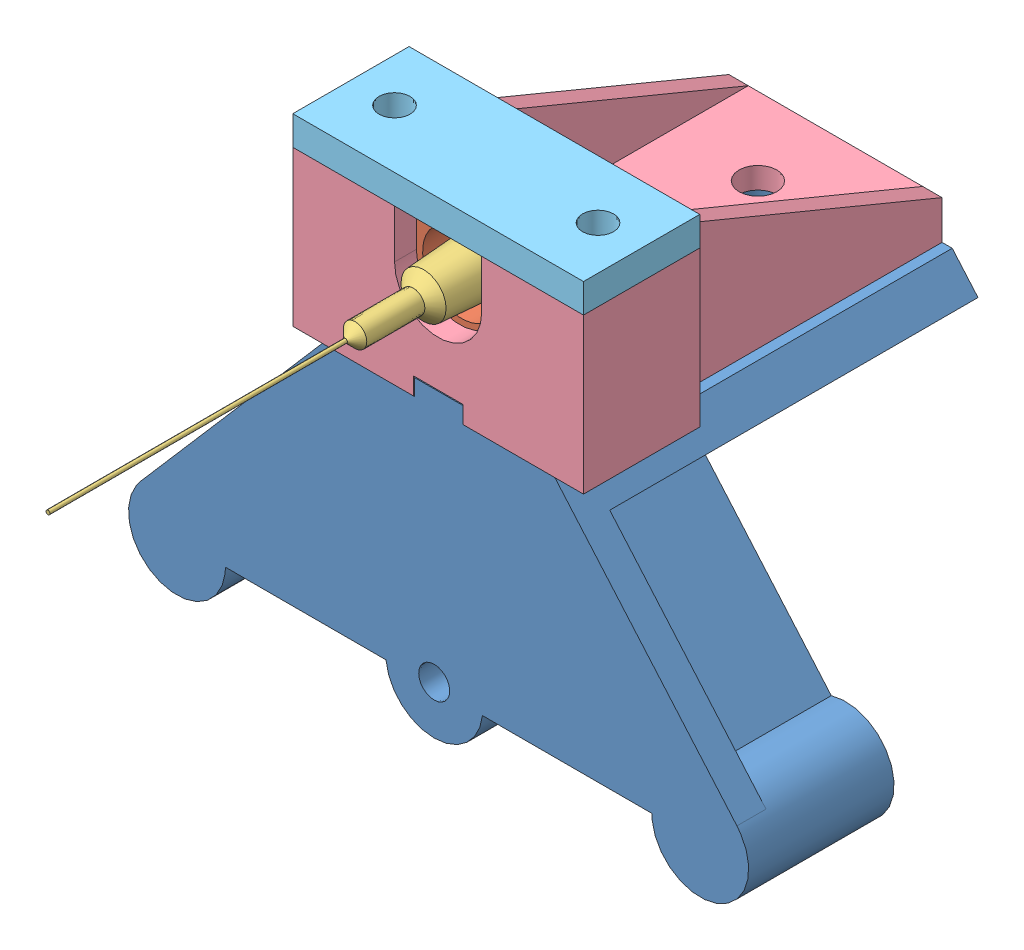
SolidWorks assembly Assem1, configuration Default. Lengths in mm.
Overall size (64 49 81.26).
5 component instances, 5 part files, 12 mates.
Components (placement in the parent):
- zsyringemount-1: zsyringemount [Default] at (-46.8974 -6.7541 42.4644) size (64 31.7 41)
- needleluer-1: needleluer [Default] at (-46.9474 29.2459 32.4644) x (-0.940606 -0.3395 0) z (-0.3395 0.940606 0) size (11.07 15.1 11.07)
- needle-1: needle [Default] at (-46.9474 29.2459 33.6644) size (6.67 6.67 49.06)
- luerholder-1: luerholder [Default] at (-37.228 -6.7541 30.4644) x (-1 0 0) z (0 0 -1) size (30 16 41)
- luerholderclamp-1: luerholderclamp [Default] at (-37.228 34.2459 30.4644) x (-1 0 0) z (0 1 0) size (30 12 3)
Mates (geometry in assembly coordinates):
- Parallel1: parallel aligned: plane of zsyringemount-1 through (-19.8974 -6.7541 42.4644) normal (0 0 1); plane of needleluer-1 through (-46.9474 29.2459 42.5644) normal (0 0 1)
- Concentric1: concentric anti-aligned: cylinder of needleluer-1 through (-46.9474 29.2459 42.5644) axis (0 0 -1) radius 2.3078; cylinder of needle-1 through (-46.9474 29.2459 82.7244) axis (0 0 1) radius 3.335
- Coincident2: coincident anti-aligned: plane of needleluer-1 through (-46.9474 29.2459 33.6644) normal (0 0 1); plane of needle-1 through (-46.9474 29.2459 33.6644) normal (0 0 -1)
- Coincident6: coincident anti-aligned: plane of zsyringemount-1 through (-58.8974 18.2459 39.4644) normal (0 1 0); plane of luerholder-1 through (-61.9474 18.2459 42.4644) normal (0 -1 0)
- Distance1: distance = 0.1 mm anti-aligned: plane of luerholder-1 through (-49.4974 18.2459 42.4644) normal (1 0 0); plane of zsyringemount-1 through (-49.3974 18.2459 42.4644) normal (-1 0 0)
- Concentric2: concentric aligned: cylinder of needleluer-1 through (-46.9474 29.2459 40.0644) axis (0 0 -1) radius 5.535; cylinder of luerholder-1 through (-46.9474 29.2459 42.4644) axis (0 0 -1) radius 4.5
- Coincident9: coincident aligned: plane of zsyringemount-1 through (-19.8974 -6.7541 42.4644) normal (0 0 1); plane of luerholder-1 through (-46.9474 29.2459 42.4644) normal (0 0 1)
- Coincident10: coincident anti-aligned: plane of needleluer-1 through (-46.9474 29.2459 32.4644) normal (0 0 -1); plane of luerholder-1 through (-46.9474 29.2459 32.4644) normal (0 0 1)
- InPlace2: in place: plane of luerholder-1 through (-49.9474 34.2459 42.4644) normal (0 1 0); plane of ? through (0 34.2459 0) normal (0 1 0); moOrthogonalPlaneRef_w of luerholder-1 through (-49.9474 34.2459 42.4644) normal (0 1 0); plane of ? through (0 34.2459 0) normal (0 0 -1); plane of luerholder-1 through (-49.9474 34.2459 42.4644) normal (0 1 0); line of ? through (-55 0 34.2459) axis (0 1 0); plane of luerholder-1 through (-51.4474 34.2459 42.4644) normal (0 1 0); unknown of luerholderclamp-1
- Coincident11: coincident aligned: plane of luerholder-1; plane of luerholderclamp-1
- Coincident12: coincident aligned: moOrthogonalPlaneRef_w of luerholder-1 through (-37.228 34.2459 30.4644) normal (0 0 1); plane of luerholderclamp-1
- Coincident13: coincident anti-aligned: moOrthogonalPlaneRef_w of luerholder-1 through (-37.228 34.2459 30.4644) normal (1 0 0); plane of luerholderclamp-1
